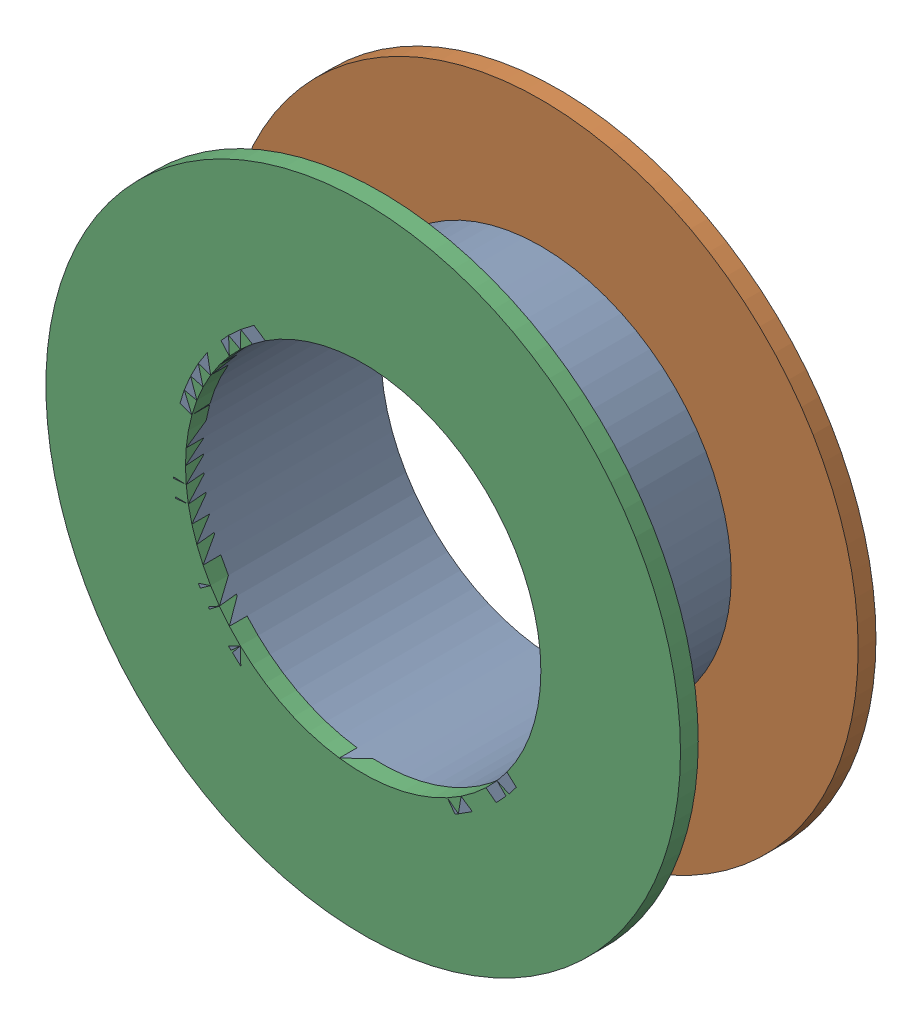
SolidWorks assembly Via (17.2mm,58.1mm) from Top Layer to Bottom Layer, configuration Predeterminado. Lengths in mm.
Overall size (1.27 1.27 0.39).
6 component instances, 2 part files, 0 mates.
Components (placement in the parent):
- Via Hole-1: Via Hole [Predeterminado] at (17.2 58.1 -0.4013) size (0.76 0.76 0.39)
  - Via Hole-Part-1-1: Via Hole-Part-1 [Predeterminado] at origin size (0.76 0.76 0.39)
- Via Top Layer-1: Via Top Layer [Predeterminado] at (17.2 58.1 -0.4013) size (1.27 1.27 0.04)
  - Via Top Layer-Part-1-1: Via Top Layer-Part-1 [Predeterminado] at origin size (1.27 1.27 0.04)
- Via Top Layer-2: Via Top Layer [Predeterminado] at (17.2 58.1 -0.0457) size (1.27 1.27 0.04)
  - Via Top Layer-Part-1-1: Via Top Layer-Part-1 [Predeterminado] at origin size (1.27 1.27 0.04)
